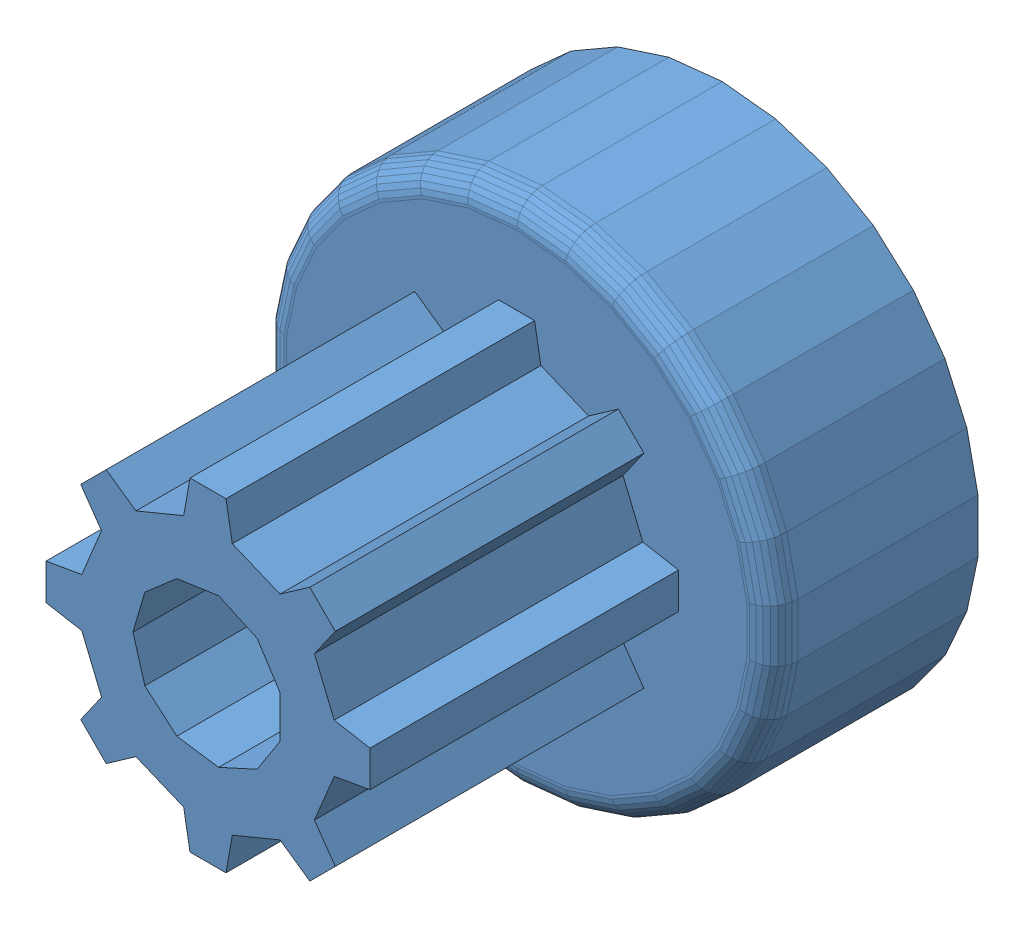
SolidWorks assembly 110607.04 Pulley, configuration Default. Lengths in mm.
Overall size (19.89 20 20).
3 component instances, 3 part files, 5 mates.
Components (placement in the parent):
- pulley-1: pulley [Default] at origin size (19.89 20 20)
- hex nut, DIN 934-1: hex nut, DIN 934 [M04x0.7] at (-2.9445 -1.7 4) x (0.5 -0.866025 0) z (-0.866025 -0.5 0) size (8.08 7 3.2)
- set screw, cup point, M4x6-1: set screw, cup point, M4x6 [Default] at (-2.1651 -1.25 4) x (0 0 1) z (-0.866025 -0.5 0) size (4 4 6.12)
Mates (geometry in assembly coordinates):
- Coincident125: coincident aligned: line of pulley-1 through (0 0 4) axis (-0.866025 -0.5 0); line of hex nut, DIN 934-1 through (-15.1657 -8.7559 4) axis (-0.866025 -0.5 0)
- Coincident127: coincident: point of pulley-1; plane of hex nut, DIN 934-1 through (-2.9445 -1.7 4) normal (0.866025 0.5 0)
- Parallel1: parallel: line of pulley-1 through (0 0 0) axis (0 0 1); plane of hex nut, DIN 934-1
- Coincident129: coincident aligned: line of pulley-1 through (0 0 4) axis (-0.866025 -0.5 0); line of set screw, cup point, M4x6-1 through (-14.3863 -8.3059 4) axis (-0.866025 -0.5 0)
- Coincident130: coincident: point of pulley-1; plane of set screw, cup point, M4x6-1 through (-2.1651 -1.25 4) normal (-0.866025 -0.5 0)
